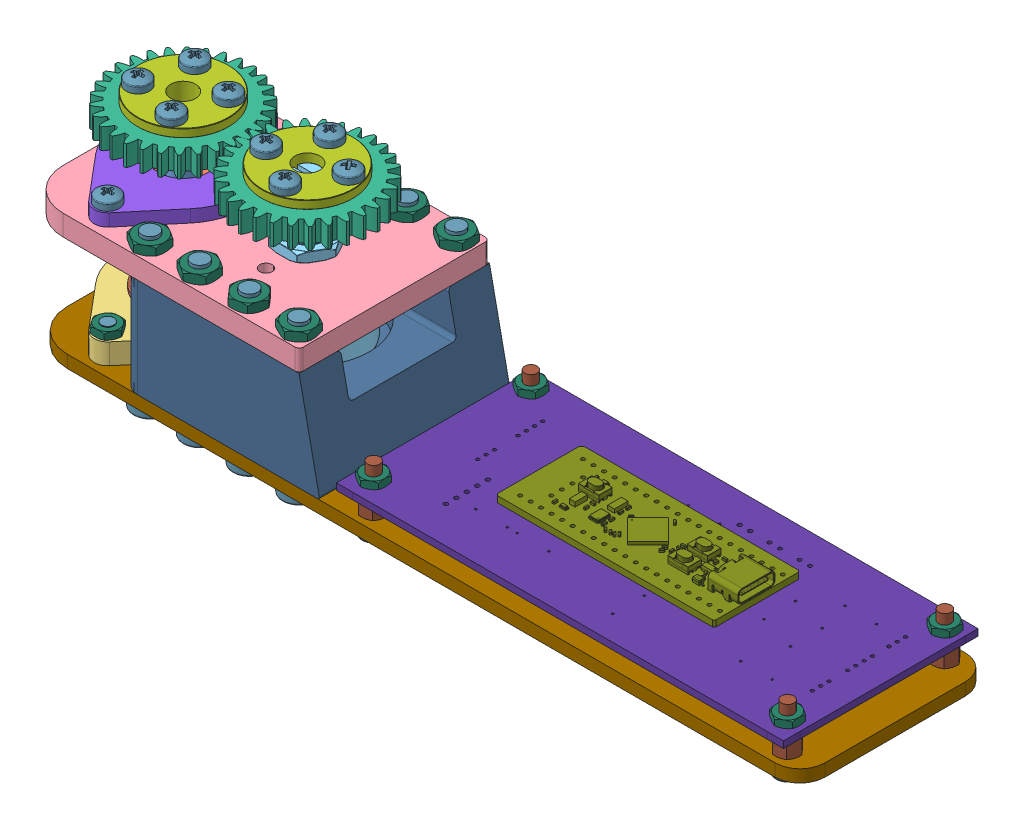
SolidWorks assembly phan_cang_tay_asm, configuration Default. Lengths in mm.
Overall size (193.86 57.82 47.69).
87 component instances, 17 part files, 172 mates.
Components (placement in the parent):
- truc_khuy_tay_6mm-1: truc_khuy_tay_6mm [Default] at (-13.0536 7.0359 41.2843) size (6 45 6)
- instrument ball bearing_68_am-1: instrument ball bearing_68_am [AFBMA 12.1.4.1 - 0060-19 - 8,DE,NC,8_68] at (-13.0536 10.0359 41.2843) x (0 -1 0) z (0.814441 0 0.580247) size (6 19 19)
- instrument ball bearing_68_am-2: instrument ball bearing_68_am [AFBMA 12.1.4.1 - 0060-19 - 8,DE,NC,8_68] at (-13.0536 33.0359 41.2843) x (0 -1 0) z (0.463151 0 0.88628) size (6 19 19)
- thanh_noi_cang_tay_1-1: thanh_noi_cang_tay_1 [Default] at (-13.0536 7.0359 41.2843) x (-1 0 0) z (0 0 -1) size (30 5 43)
- khuy_tay-1: khuy_tay [Default] at (16.9464 36.0359 41.2843) x (-1 0 0) z (0 -1 0) size (67 46 5)
- RV24 v6.step-1: RV24 v6.step [Default] at (16.9464 24.0359 41.2843) x (0 1 0) z (0 0 -1) size (34 30.6 24.6)
- banh_rang-1: banh_rang [Default] at (-13.8942 39.1454 73.2027) x (0 1 0) z (-0.508693 0 -0.860948) size (12 31.88 32)
  - spur gear_iso_m3-1: spur gear_iso_m3 [ISO - Spur gear 1M 30T 20PA 10FW ---S30B25H18L6.0N] at (1.8905 16.9604 27.0525) size (5 31.88 32)
  - mat_bich_6mm-1: mat_bich_6mm [Default] at (13.8905 16.9604 27.0525) x (0 0 1) z (0 -1 0) size (22 12 22)
- mieng_che_o_lan-1: mieng_che_o_lan [Default] at (-13.0536 36.0359 41.2843) x (-1 0 0) z (0 0 -1) size (30 3 43)
- thanh_cang_tay-1: thanh_cang_tay [Default] at (102.9464 4.0359 41.2843) x (-1 0 0) z (0 1 0) size (187 46 3)
- noi_cang_tay-1: noi_cang_tay [Default] at (21.9464 7.0359 41.2843) x (-1 0 0) z (0 0 -1) size (47.89 24 46)
- hexagonal_spacer_MF_M3_H05_HEX5_FTD3_MTL8.step-2: hexagonal_spacer_MF_M3_H05_HEX5_FTD3_MTL8.step [Default] at (151.9464 12.0359 60.2843) x (-0.310043 0 0.950723) z (0 -1 0) size (5.78 5.01 10.97)
- mieng_dem_cang_tay-1: mieng_dem_cang_tay [Default] at (117.9464 4.0359 41.2843) x (-1 0 0) z (0 0 -1) size (70 6.47 35)
- mieng_dem_cang_tay_2-1: mieng_dem_cang_tay_2 [Default] at (30.9464 4.0359 41.2843) x (-1 0 0) z (0 0 -1) size (68 6.47 30)
- pan head cross recess screw_iso-1: pan head cross recess screw_iso [ISO 7045 - M3 x 8 - Z - 8N] at (147.9464 -0.3641 27.2843) x (0 1 0) z (0 0 1) size (10.35 5.6 5.6)
- pan head cross recess screw_iso-2: pan head cross recess screw_iso [ISO 7045 - M3 x 8 - Z - 8N] at (147.9464 -0.3641 55.2843) x (0 1 0) z (0 0 1) size (10.35 5.6 5.6)
- pan head cross recess screw_iso-3: pan head cross recess screw_iso [ISO 7045 - M3 x 8 - Z - 8N] at (87.9464 -0.3641 55.2843) x (0 1 0) z (0 0 1) size (10.35 5.6 5.6)
- pan head cross recess screw_iso-4: pan head cross recess screw_iso [ISO 7045 - M3 x 8 - Z - 8N] at (87.9464 -0.3641 27.2843) x (0 1 0) z (0 0 1) size (10.35 5.6 5.6)
- pan head cross recess screw_iso-5: pan head cross recess screw_iso [ISO 7045 - M3 x 8 - Z - 8N] at (60.9464 -0.3641 52.2843) x (0 1 0) z (0 0 1) size (10.35 5.6 5.6)
- pan head cross recess screw_iso-6: pan head cross recess screw_iso [ISO 7045 - M3 x 8 - Z - 8N] at (60.9464 -0.3641 30.2843) x (0 1 0) z (0 0 1) size (10.35 5.6 5.6)
- pan head cross recess screw_iso-9: pan head cross recess screw_iso [ISO 7045 - M3 x 6 - Z - 6N] at (0.9464 9.4359 30.2843) x (0 -1 0) z (0 0 1) size (8.35 5.6 5.6)
- pan head cross recess screw_iso-10: pan head cross recess screw_iso [ISO 7045 - M3 x 6 - Z - 6N] at (0.9464 9.4359 52.2843) x (0 -1 0) z (0 0 1) size (8.35 5.6 5.6)
- hex thin nut chamfered gradeab_iso-3: hex thin nut chamfered gradeab_iso [ISO - 4035 - M3 - N] at (0.9464 0.2359 30.2843) x (1 0 0) z (0 -1 0) size (5.5 6.35 1.8)
- hex thin nut chamfered gradeab_iso-4: hex thin nut chamfered gradeab_iso [ISO - 4035 - M3 - N] at (0.9464 0.2359 52.2843) x (1 0 0) z (0 -1 0) size (5.5 6.35 1.8)
- hex thin nut chamfered gradeab_iso-5: hex thin nut chamfered gradeab_iso [ISO - 4035 - M3 - N] at (60.9464 8.8359 30.2843) x (1 0 0) z (0 1 0) size (5.5 6.35 1.8)
- hex thin nut chamfered gradeab_iso-6: hex thin nut chamfered gradeab_iso [ISO - 4035 - M3 - N] at (60.9464 8.8359 52.2843) x (1 0 0) z (0 1 0) size (5.5 6.35 1.8)
- hex thin nut chamfered gradeab_iso-7: hex thin nut chamfered gradeab_iso [ISO - 4035 - M3 - N] at (87.9464 8.8359 55.2843) x (1 0 0) z (0 1 0) size (5.5 6.35 1.8)
- hex thin nut chamfered gradeab_iso-8: hex thin nut chamfered gradeab_iso [ISO - 4035 - M3 - N] at (87.9464 8.8359 27.2843) x (1 0 0) z (0 1 0) size (5.5 6.35 1.8)
- hex thin nut chamfered gradeab_iso-9: hex thin nut chamfered gradeab_iso [ISO - 4035 - M3 - N] at (147.9464 8.8359 27.2843) x (1 0 0) z (0 1 0) size (5.5 6.35 1.8)
- hex thin nut chamfered gradeab_iso-10: hex thin nut chamfered gradeab_iso [ISO - 4035 - M3 - N] at (147.9464 8.8359 55.2843) x (1 0 0) z (0 1 0) size (5.5 6.35 1.8)
- pan head cross recess screw_iso-18: pan head cross recess screw_iso [ISO 7045 - M4 x 35 - Z - 35N] at (33.9464 0.9359 22.2843) x (0 1 0) z (0 0 1) size (38.02 8 8)
- pan head cross recess screw_iso-19: pan head cross recess screw_iso [ISO 7045 - M4 x 35 - Z - 35N] at (21.9464 0.9359 22.2843) x (0 1 0) z (0 0 1) size (38.02 8 8)
- pan head cross recess screw_iso-20: pan head cross recess screw_iso [ISO 7045 - M4 x 35 - Z - 35N] at (9.9464 0.9359 22.2843) x (0 1 0) z (0 0 1) size (38.02 8 8)
- pan head cross recess screw_iso-21: pan head cross recess screw_iso [ISO 7045 - M4 x 35 - Z - 35N] at (33.9464 0.9359 60.2843) x (0 1 0) z (0 0 1) size (38.02 8 8)
- pan head cross recess screw_iso-22: pan head cross recess screw_iso [ISO 7045 - M4 x 35 - Z - 35N] at (21.9464 0.9359 60.2843) x (0 1 0) z (0 0 1) size (38.02 8 8)
- pan head cross recess screw_iso-23: pan head cross recess screw_iso [ISO 7045 - M4 x 35 - Z - 35N] at (9.9464 0.9359 60.2843) x (0 1 0) z (0.916024 0 0.401125) size (38.02 8 8)
- hex thin nut chamfered gradeab_iso-11: hex thin nut chamfered gradeab_iso [ISO - 4035 - M4 - N] at (33.9464 38.2359 22.2843) x (1 0 0) z (0 1 0) size (7 8.08 2.2)
- hex thin nut chamfered gradeab_iso-12: hex thin nut chamfered gradeab_iso [ISO - 4035 - M4 - N] at (21.9464 38.2359 22.2843) x (1 0 0) z (0 1 0) size (7 8.08 2.2)
- hex thin nut chamfered gradeab_iso-13: hex thin nut chamfered gradeab_iso [ISO - 4035 - M4 - N] at (9.9464 38.2359 22.2843) x (1 0 0) z (0 1 0) size (7 8.08 2.2)
- hex thin nut chamfered gradeab_iso-14: hex thin nut chamfered gradeab_iso [ISO - 4035 - M4 - N] at (33.9464 36.0359 60.2843) x (0.993976 0 -0.109599) z (0 -1 0) size (7 8.08 2.2)
- hex thin nut chamfered gradeab_iso-15: hex thin nut chamfered gradeab_iso [ISO - 4035 - M4 - N] at (21.9464 38.2359 60.2843) x (-0.185733 0 -0.9826) z (0 1 0) size (7 8.08 2.2)
- hex thin nut chamfered gradeab_iso-16: hex thin nut chamfered gradeab_iso [ISO - 4035 - M4 - N] at (9.9464 38.2359 60.2843) x (1 0 0) z (0 1 0) size (7 8.08 2.2)
- pan head cross recess screw_iso-25: pan head cross recess screw_iso [ISO 7045 - M3 x 10 - Z - 10N] at (-6.166 55.4359 37.2148) x (0 -1 0) z (0 0 1) size (12.35 5.6 5.6)
- pan head cross recess screw_iso-26: pan head cross recess screw_iso [ISO 7045 - M3 x 10 - Z - 10N] at (-8.9841 55.4359 48.1719) x (0 -1 0) z (0 0 1) size (12.35 5.6 5.6)
- pan head cross recess screw_iso-27: pan head cross recess screw_iso [ISO 7045 - M3 x 10 - Z - 10N] at (-19.9412 55.4359 45.3539) x (0 -1 0) z (-0.140483 0 -0.990083) size (12.35 5.6 5.6)
- pan head cross recess screw_iso-28: pan head cross recess screw_iso [ISO 7045 - M3 x 10 - Z - 10N] at (-17.1232 55.4359 34.3967) x (0 -1 0) z (0 0 1) size (12.35 5.6 5.6)
- pan head cross recess screw_iso-29: pan head cross recess screw_iso [ISO 7045 - M3 x 10 - Z - 10N] at (24.6096 55.4359 38.9877) x (0 -1 0) z (-0.805474 0 0.592631) size (12.35 5.6 5.6)
- pan head cross recess screw_iso-30: pan head cross recess screw_iso [ISO 7045 - M3 x 10 - Z - 10N] at (14.6497 55.4359 33.6211) x (0 -1 0) z (0 0 1) size (12.35 5.6 5.6)
- pan head cross recess screw_iso-31: pan head cross recess screw_iso [ISO 7045 - M3 x 10 - Z - 10N] at (9.2831 55.4359 43.581) x (0 -1 0) z (0 0 1) size (12.35 5.6 5.6)
- pan head cross recess screw_iso-32: pan head cross recess screw_iso [ISO 7045 - M3 x 10 - Z - 10N] at (19.243 55.4359 48.9476) x (0 -1 0) z (0 0 1) size (12.35 5.6 5.6)
- banh_rang-3: banh_rang [Default] at (47.7291 39.1454 49.7644) x (0 1 0) z (-0.957906 0 0.287083) size (12 31.88 32)
  - spur gear_iso_m3-1: spur gear_iso_m3 [ISO - Spur gear 1M 30T 20PA 10FW ---S30B25H18L6.0N] at (1.8905 16.9604 27.0525) size (5 31.88 32)
  - mat_bich_6mm-1: mat_bich_6mm [Default] at (13.8905 16.9604 27.0525) x (0 0 1) z (0 -1 0) size (22 12 22)
- hex thin nut chamfered gradeab_iso-18: hex thin nut chamfered gradeab_iso [ISO - 4035 - M3 - N] at (19.243 44.2359 48.9476) x (1 0 0) z (0 -1 0) size (5.5 6.35 1.8)
- hex thin nut chamfered gradeab_iso-19: hex thin nut chamfered gradeab_iso [ISO - 4035 - M3 - N] at (9.2831 44.2359 43.581) x (1 0 0) z (0 -1 0) size (5.5 6.35 1.8)
- hex thin nut chamfered gradeab_iso-20: hex thin nut chamfered gradeab_iso [ISO - 4035 - M3 - N] at (14.6497 44.2359 33.6211) x (1 0 0) z (0 -1 0) size (5.5 6.35 1.8)
- hex thin nut chamfered gradeab_iso-21: hex thin nut chamfered gradeab_iso [ISO - 4035 - M3 - N] at (24.6096 44.2359 38.9877) x (1 0 0) z (0 -1 0) size (5.5 6.35 1.8)
- hex thin nut chamfered gradeab_iso-22: hex thin nut chamfered gradeab_iso [ISO - 4035 - M3 - N] at (-6.166 44.2359 37.2148) x (1 0 0) z (0 -1 0) size (5.5 6.35 1.8)
- hex thin nut chamfered gradeab_iso-23: hex thin nut chamfered gradeab_iso [ISO - 4035 - M3 - N] at (-8.9841 44.2359 48.1719) x (1 0 0) z (0 -1 0) size (5.5 6.35 1.8)
- hex thin nut chamfered gradeab_iso-24: hex thin nut chamfered gradeab_iso [ISO - 4035 - M3 - N] at (-17.1232 44.2359 34.3967) x (1 0 0) z (0 -1 0) size (5.5 6.35 1.8)
- hex thin nut chamfered gradeab_iso-25: hex thin nut chamfered gradeab_iso [ISO - 4035 - M3 - N] at (-19.9412 44.2359 45.3539) x (1 0 0) z (0 -1 0) size (5.5 6.35 1.8)
- pan head cross recess screw_iso-37: pan head cross recess screw_iso [ISO 7045 - M3 x 10 - Z - 10N] at (-13.0536 41.4359 59.5343) x (0 -1 0) z (0 0 1) size (12.35 5.6 5.6)
- pan head cross recess screw_iso-38: pan head cross recess screw_iso [ISO 7045 - M3 x 10 - Z - 10N] at (-13.0536 41.4359 23.0343) x (0 -1 0) z (0 0 1) size (12.35 5.6 5.6)
- pan head cross recess screw_iso-39: pan head cross recess screw_iso [ISO 7045 - M3 x 10 - Z - 10N] at (-13.0536 1.6359 59.5343) x (0 1 0) z (0 0 1) size (12.35 5.6 5.6)
- pan head cross recess screw_iso-40: pan head cross recess screw_iso [ISO 7045 - M3 x 10 - Z - 10N] at (-13.0536 1.6359 23.0343) x (0 1 0) z (0 0 1) size (12.35 5.6 5.6)
- hex thin nut chamfered gradeab_iso-30: hex thin nut chamfered gradeab_iso [ISO - 4035 - M3 - N] at (-13.0536 29.2359 23.0343) x (1 0 0) z (0 -1 0) size (5.5 6.35 1.8)
- hex thin nut chamfered gradeab_iso-31: hex thin nut chamfered gradeab_iso [ISO - 4035 - M3 - N] at (-13.0536 13.8359 23.0343) x (1 0 0) z (0 1 0) size (5.5 6.35 1.8)
- hex thin nut chamfered gradeab_iso-33: hex thin nut chamfered gradeab_iso [ISO - 4035 - M3 - N] at (-13.0536 12.0359 59.5343) x (0.832178 0 -0.554509) z (0 -1 0) size (5.5 6.35 1.8)
- hex thin nut chamfered gradeab_iso-34: hex thin nut chamfered gradeab_iso [ISO - 4035 - M3 - N] at (-13.0536 29.2359 59.5343) x (1 0 0) z (0 -1 0) size (5.5 6.35 1.8)
- pan head cross recess screw_iso-59: pan head cross recess screw_iso [ISO 7045 - M4 x 35 - Z - 35N] at (-2.0536 0.9359 60.2843) x (0 1 0) z (-0.660079 0 0.751196) size (38.02 8 8)
- hex thin nut chamfered gradeab_iso-45: hex thin nut chamfered gradeab_iso [ISO - 4035 - M4 - N] at (-2.0536 38.2359 60.2843) x (1 0 0) z (0 1 0) size (7 8.08 2.2)
- hexagonal_spacer_MF_M3_H05_HEX5_FTD3_MTL8.step-3: hexagonal_spacer_MF_M3_H05_HEX5_FTD3_MTL8.step [Default] at (151.9464 12.0359 22.2843) x (-0.310043 0 0.950723) z (0 -1 0) size (5.78 5.01 10.97)
- hexagonal_spacer_MF_M3_H05_HEX5_FTD3_MTL8.step-4: hexagonal_spacer_MF_M3_H05_HEX5_FTD3_MTL8.step [Default] at (51.9464 12.0359 60.2843) x (-0.310043 0 0.950723) z (0 -1 0) size (5.78 5.01 10.97)
- hexagonal_spacer_MF_M3_H05_HEX5_FTD3_MTL8.step-5: hexagonal_spacer_MF_M3_H05_HEX5_FTD3_MTL8.step [Default] at (51.9464 12.0359 22.2843) x (-0.310043 0 0.950723) z (0 -1 0) size (5.78 5.01 10.97)
- pan head cross recess screw_iso-60: pan head cross recess screw_iso [ISO 7045 - M3 x 8 - Z - 8N] at (151.9464 1.6359 22.2843) x (0 1 0) z (0 0 1) size (10.35 5.6 5.6)
- pan head cross recess screw_iso-61: pan head cross recess screw_iso [ISO 7045 - M3 x 8 - Z - 8N] at (151.9464 1.6359 60.2843) x (0 1 0) z (0 0 1) size (10.35 5.6 5.6)
- pan head cross recess screw_iso-62: pan head cross recess screw_iso [ISO 7045 - M3 x 8 - Z - 8N] at (51.9464 1.6359 60.2843) x (0 1 0) z (0 0 1) size (10.35 5.6 5.6)
- pan head cross recess screw_iso-63: pan head cross recess screw_iso [ISO 7045 - M3 x 8 - Z - 8N] at (51.9464 1.6359 22.2843) x (0 1 0) z (0 0 1) size (10.35 5.6 5.6)
- control_glove_v0.1.step-1: control_glove_v0.1.step [Default] at (56.9464 12.0359 56.2843) x (1 0 0) z (0 1 0) size (108 47 7.4)
  - MiniF4x1Cx_V31_3D.step-1: MiniF4x1Cx_V31_3D.step [Default] at (68.0647 25.992 4.15) x (-1 0 0) z (0 0 1) size (52.81 20.78 5.3)
    - COMPOUND.step-1: COMPOUND.step [Default] at origin size (52.81 20.78 5.3)
  - _autosave-control_glove_v0.1 PCB.step-1: _autosave-control_glove_v0.1 PCB.step [Default] at origin size (108 47 1.6)
- hex thin nut chamfered gradeab_iso-46: hex thin nut chamfered gradeab_iso [ISO - 4035 - M3 - N] at (51.9464 15.4359 22.2843) x (1 0 0) z (0 1 0) size (5.5 6.35 1.8)
- hex thin nut chamfered gradeab_iso-47: hex thin nut chamfered gradeab_iso [ISO - 4035 - M3 - N] at (51.9464 15.4359 60.2843) x (1 0 0) z (0 1 0) size (5.5 6.35 1.8)
- hex thin nut chamfered gradeab_iso-48: hex thin nut chamfered gradeab_iso [ISO - 4035 - M3 - N] at (151.9464 15.4359 22.2843) x (1 0 0) z (0 1 0) size (5.5 6.35 1.8)
- hex thin nut chamfered gradeab_iso-49: hex thin nut chamfered gradeab_iso [ISO - 4035 - M3 - N] at (151.9464 15.4359 60.2843) x (1 0 0) z (0 1 0) size (5.5 6.35 1.8)
Mates (geometry in assembly coordinates):
- Concentric11: concentric aligned: cylinder of truc_khuy_tay_6mm-1 through (-13.0536 52.0359 41.2843) axis (0 -1 0) radius 3; cylinder of instrument ball bearing_68_am-1 through (-13.0536 30.6734 41.2843) axis (0 -1 0) radius 3
- Coincident1: coincident aligned: plane of truc_khuy_tay_6mm-1 through (-13.0536 7.0359 41.2843) normal (0 -1 0); plane of instrument ball bearing_68_am-1 through (-11.1388 7.0359 38.5967) normal (0 -1 0)
- Concentric6: concentric aligned: cylinder of truc_khuy_tay_6mm-1 through (-13.0536 52.0359 41.2843) axis (0 -1 0) radius 3; cylinder of instrument ball bearing_68_am-2 through (-13.0536 53.6734 41.2843) axis (0 -1 0) radius 3
- Concentric8: concentric aligned: cylinder of instrument ball bearing_68_am-1 through (-13.0536 30.6734 41.2843) axis (0 -1 0) radius 9.5; cylinder of thanh_noi_cang_tay_1-1 through (-13.0536 12.0359 41.2843) axis (0 -1 0) radius 9.5
- Concentric9: concentric anti-aligned: cylinder of instrument ball bearing_68_am-2 through (-13.0536 53.6734 41.2843) axis (0 -1 0) radius 9.5; cylinder of khuy_tay-1 through (-13.0536 31.0359 41.2843) axis (0 1 0) radius 9.5
- Concentric10: concentric aligned: cylinder of khuy_tay-1 through (16.9464 31.0359 41.2843) axis (0 1 0) radius 4.6; cylinder of RV24 v6.step-1 through (16.9464 41.0359 41.2843) axis (0 1 0) radius 3
- Distance2: distance = 19 mm anti-aligned: plane of thanh_noi_cang_tay_1-1 through (-13.0536 12.0359 41.2843) normal (0 1 0); plane of khuy_tay-1 through (16.9464 31.0359 41.2843) normal (0 -1 0)
- Concentric16: concentric aligned: cylinder of truc_khuy_tay_6mm-1 through (-13.0536 52.0359 41.2843) axis (0 -1 0) radius 3; cylinder of banh_rang-1/6mm Rigid Flange Coupling v2.step-1 through (-13.0536 50.0359 41.2843) axis (0 -1 0) radius 3
- Coincident34: coincident aligned: plane of instrument ball bearing_68_am-1 through (-7.7154 7.0359 33.7915) normal (0 -1 0); plane of thanh_noi_cang_tay_1-1 through (-13.0536 7.0359 41.2843) normal (0 -1 0)
- Concentric21: concentric aligned: cylinder of truc_khuy_tay_6mm-1 through (-13.0536 52.0359 41.2843) axis (0 -1 0) radius 3; cylinder of mieng_che_o_lan-1 through (-13.0536 39.0359 41.2843) axis (0 -1 0) radius 6
- Coincident35: coincident anti-aligned: plane of thanh_noi_cang_tay_1-1 through (-13.0536 7.0359 41.2843) normal (0 -1 0); plane of thanh_cang_tay-1 through (102.9464 7.0359 41.2843) normal (0 1 0)
- Concentric22: concentric anti-aligned: cylinder of thanh_noi_cang_tay_1-1 through (-13.0536 12.0359 41.2843) axis (0 -1 0) radius 15; cylinder of thanh_cang_tay-1 through (-13.0536 4.0359 41.2843) axis (0 1 0) radius 6
- Parallel8: parallel aligned: plane of RV24 v6.step-1 through (33.7464 28.5359 41.7843) normal (0 0 -1); plane of thanh_cang_tay-1 through (102.9464 7.0359 18.2843) normal (0 0 -1)
- Coincident46: coincident anti-aligned: plane of thanh_cang_tay-1 through (102.9464 7.0359 41.2843) normal (0 1 0); plane of noi_cang_tay-1 through (21.9464 7.0359 41.2843) normal (0 -1 0)
- Concentric40: concentric anti-aligned: cylinder of khuy_tay-1 through (-13.0536 31.0359 23.0343) axis (0 1 0) radius 1.5; cylinder of mieng_che_o_lan-1 through (-13.0536 39.0359 23.0343) axis (0 -1 0) radius 1.5
- Coincident50: coincident anti-aligned: plane of khuy_tay-1 through (16.9464 36.0359 41.2843) normal (0 1 0); plane of mieng_che_o_lan-1 through (-13.0536 36.0359 41.2843) normal (0 -1 0)
- Concentric41: concentric anti-aligned: cylinder of truc_khuy_tay_6mm-1 through (-13.0536 52.0359 41.2843) axis (0 -1 0) radius 3; cylinder of banh_rang-1/mat_bich_6mm-1 through (-13.0536 51.0359 41.2843) axis (0 1 0) radius 3
- Coincident52: coincident anti-aligned: plane of khuy_tay-1 through (16.9464 31.0359 41.2843) normal (0 -1 0); plane of RV24 v6.step-1 through (16.9667 31.0359 41.2843) normal (0 1 0)
- Coincident55: coincident anti-aligned: plane of instrument ball bearing_68_am-2 through (-6.3622 36.0359 37.7875) normal (0 1 0); plane of mieng_che_o_lan-1 through (-13.0536 36.0359 41.2843) normal (0 -1 0)
- Concentric51: concentric aligned: cylinder of khuy_tay-1 through (33.9464 41.0359 22.2843) axis (0 -1 0) radius 2; cylinder of noi_cang_tay-1 through (33.9464 31.0359 22.2843) axis (0 -1 0) radius 2
- Coincident57: coincident anti-aligned: plane of thanh_cang_tay-1 through (102.9464 7.0359 41.2843) normal (0 1 0); plane of noi_cang_tay-1 through (21.9464 7.0359 41.2843) normal (0 -1 0)
- Parallel9: parallel aligned: plane of thanh_cang_tay-1 through (102.9464 7.0359 64.2843) normal (0 0 1); plane of noi_cang_tay-1 through (21.9464 31.0359 64.2843) normal (0 0 1)
- Parallel11: parallel aligned: plane of khuy_tay-1 through (37.9464 36.0359 41.2843) normal (1 0 0); plane of thanh_cang_tay-1 through (158.9464 7.0359 41.2843) normal (1 0 0)
- Concentric54: concentric anti-aligned: cylinder of thanh_noi_cang_tay_1-1 through (-13.0536 12.0359 23.0343) axis (0 -1 0) radius 1.5; cylinder of thanh_cang_tay-1 through (-13.0536 4.0359 23.0343) axis (0 1 0) radius 1.5
- Concentric59: concentric anti-aligned: cylinder of thanh_cang_tay-1 through (151.9464 4.0359 60.2843) axis (0 1 0) radius 1.5; cylinder of hexagonal_spacer_MF_M3_H05_HEX5_FTD3_MTL8.step-2 through (151.9464 19.8569 60.2843) axis (0 -1 0) radius 1.5
- Coincident72: coincident anti-aligned: plane of thanh_cang_tay-1 through (102.9464 7.0359 41.2843) normal (0 1 0); plane of hexagonal_spacer_MF_M3_H05_HEX5_FTD3_MTL8.step-2 through (151.9464 7.0359 60.2843) normal (0 -1 0)
- Parallel16: parallel aligned: plane of thanh_cang_tay-1 through (158.9464 7.0359 41.2843) normal (1 0 0); plane of mieng_dem_cang_tay-1 through (152.9464 4.0359 41.2843) normal (1 0 0)
- Coincident77: coincident anti-aligned: plane of thanh_cang_tay-1 through (102.9464 4.0359 41.2843) normal (0 -1 0); plane of mieng_dem_cang_tay-1 through (117.9464 4.0359 41.2843) normal (0 1 0)
- Concentric62: concentric anti-aligned: cylinder of thanh_cang_tay-1 through (147.9464 7.0359 27.2843) axis (0 -1 0) radius 1.6; cylinder of mieng_dem_cang_tay-1 through (147.9464 -5.9641 27.2843) axis (0 1 0) radius 1.5
- Concentric63: concentric anti-aligned: cylinder of thanh_cang_tay-1 through (60.9464 7.0359 30.2843) axis (0 -1 0) radius 1.5; cylinder of mieng_dem_cang_tay_2-1 through (60.9464 -5.9641 30.2843) axis (0 1 0) radius 1.5
- Parallel17: parallel aligned: plane of thanh_cang_tay-1 through (158.9464 7.0359 41.2843) normal (1 0 0); plane of mieng_dem_cang_tay_2-1 through (64.9464 4.0359 41.2843) normal (1 0 0)
- Coincident80: coincident anti-aligned: plane of thanh_cang_tay-1 through (102.9464 4.0359 41.2843) normal (0 -1 0); plane of mieng_dem_cang_tay_2-1 through (30.9464 4.0359 41.2843) normal (0 1 0)
- Concentric85: concentric anti-aligned: cylinder of mieng_dem_cang_tay-1 through (147.9464 -5.9641 27.2843) axis (0 1 0) radius 1.5; cylinder of pan head cross recess screw_iso-1 through (147.9464 -25.7641 27.2843) axis (0 -1 0) radius 2.8
- Coincident88: coincident anti-aligned: plane of mieng_dem_cang_tay-1 through (152.9464 2.0359 41.2843) normal (0 -1 0); plane of pan head cross recess screw_iso-1 through (146.4464 2.0359 27.2843) normal (0 1 0)
- Concentric86: concentric anti-aligned: cylinder of mieng_dem_cang_tay-1 through (147.9464 -5.9641 55.2843) axis (0 1 0) radius 1.5; cylinder of pan head cross recess screw_iso-2 through (147.9464 -25.7641 55.2843) axis (0 -1 0) radius 2.8
- Coincident89: coincident anti-aligned: plane of mieng_dem_cang_tay-1 through (152.9464 2.0359 41.2843) normal (0 -1 0); plane of pan head cross recess screw_iso-2 through (146.4464 2.0359 55.2843) normal (0 1 0)
- Concentric87: concentric anti-aligned: cylinder of mieng_dem_cang_tay-1 through (87.9464 -5.9641 55.2843) axis (0 1 0) radius 1.5; cylinder of pan head cross recess screw_iso-3 through (87.9464 -25.7641 55.2843) axis (0 -1 0) radius 2.8
- Coincident90: coincident anti-aligned: plane of mieng_dem_cang_tay-1 through (82.9464 2.0359 41.2843) normal (0 -1 0); plane of pan head cross recess screw_iso-3 through (86.4464 2.0359 55.2843) normal (0 1 0)
- Concentric88: concentric anti-aligned: cylinder of mieng_dem_cang_tay-1 through (87.9464 -5.9641 27.2843) axis (0 1 0) radius 1.5; cylinder of pan head cross recess screw_iso-4 through (87.9464 -25.7641 27.2843) axis (0 -1 0) radius 2.8
- Coincident91: coincident anti-aligned: plane of mieng_dem_cang_tay-1 through (82.9464 2.0359 41.2843) normal (0 -1 0); plane of pan head cross recess screw_iso-4 through (86.4464 2.0359 27.2843) normal (0 1 0)
- Concentric89: concentric anti-aligned: cylinder of mieng_dem_cang_tay_2-1 through (60.9464 -5.9641 52.2843) axis (0 1 0) radius 1.5; cylinder of pan head cross recess screw_iso-5 through (60.9464 -25.7641 52.2843) axis (0 -1 0) radius 2.8
- Coincident92: coincident anti-aligned: plane of mieng_dem_cang_tay_2-1 through (64.9464 2.0359 41.2843) normal (0 -1 0); plane of pan head cross recess screw_iso-5 through (59.4464 2.0359 52.2843) normal (0 1 0)
- Concentric90: concentric anti-aligned: cylinder of mieng_dem_cang_tay_2-1 through (60.9464 -5.9641 30.2843) axis (0 1 0) radius 1.5; cylinder of pan head cross recess screw_iso-6 through (60.9464 -25.7641 30.2843) axis (0 -1 0) radius 2.8
- Coincident93: coincident anti-aligned: plane of mieng_dem_cang_tay_2-1 through (64.9464 2.0359 41.2843) normal (0 -1 0); plane of pan head cross recess screw_iso-6 through (59.4464 2.0359 30.2843) normal (0 1 0)
- Concentric93: concentric anti-aligned: cylinder of thanh_cang_tay-1 through (0.9464 14.0359 30.2843) axis (0 -1 0) radius 1.5; cylinder of pan head cross recess screw_iso-9 through (0.9464 34.8359 30.2843) axis (0 1 0) radius 2.8
- Coincident96: coincident anti-aligned: plane of thanh_cang_tay-1 through (102.9464 7.0359 41.2843) normal (0 1 0); plane of pan head cross recess screw_iso-9 through (2.4464 7.0359 30.2843) normal (0 -1 0)
- Concentric94: concentric anti-aligned: cylinder of thanh_cang_tay-1 through (0.9464 14.0359 52.2843) axis (0 -1 0) radius 1.5; cylinder of pan head cross recess screw_iso-10 through (0.9464 34.8359 52.2843) axis (0 1 0) radius 2.8
- Coincident97: coincident anti-aligned: plane of thanh_cang_tay-1 through (102.9464 7.0359 41.2843) normal (0 1 0); plane of pan head cross recess screw_iso-10 through (2.4464 7.0359 52.2843) normal (0 -1 0)
- Concentric96: concentric anti-aligned: cylinder of mieng_dem_cang_tay_2-1 through (0.9464 -5.9641 30.2843) axis (0 1 0) radius 1.5; cylinder of hex thin nut chamfered gradeab_iso-3 through (0.9464 25.2734 30.2843) axis (0 -1 0) radius 1.5
- Coincident99: coincident anti-aligned: plane of mieng_dem_cang_tay_2-1 through (-3.0536 2.0359 41.2843) normal (0 -1 0); plane of hex thin nut chamfered gradeab_iso-3 through (0.9464 2.0359 33.4598) normal (0 1 0)
- Concentric97: concentric anti-aligned: cylinder of mieng_dem_cang_tay_2-1 through (0.9464 -5.9641 52.2843) axis (0 1 0) radius 1.5; cylinder of hex thin nut chamfered gradeab_iso-4 through (0.9464 25.2734 52.2843) axis (0 -1 0) radius 1.5
- Coincident100: coincident anti-aligned: plane of mieng_dem_cang_tay_2-1 through (-3.0536 2.0359 41.2843) normal (0 -1 0); plane of hex thin nut chamfered gradeab_iso-4 through (0.9464 2.0359 55.4598) normal (0 1 0)
- Concentric98: concentric anti-aligned: cylinder of thanh_cang_tay-1 through (60.9464 7.0359 30.2843) axis (0 -1 0) radius 1.5; cylinder of hex thin nut chamfered gradeab_iso-5 through (60.9464 -16.2016 30.2843) axis (0 1 0) radius 1.5
- Coincident101: coincident anti-aligned: plane of thanh_cang_tay-1 through (102.9464 7.0359 41.2843) normal (0 1 0); plane of hex thin nut chamfered gradeab_iso-5 through (60.9464 7.0359 27.1089) normal (0 -1 0)
- Concentric99: concentric anti-aligned: cylinder of thanh_cang_tay-1 through (60.9464 7.0359 52.2843) axis (0 -1 0) radius 1.5; cylinder of hex thin nut chamfered gradeab_iso-6 through (60.9464 -16.2016 52.2843) axis (0 1 0) radius 1.5
- Coincident102: coincident anti-aligned: plane of thanh_cang_tay-1 through (102.9464 7.0359 41.2843) normal (0 1 0); plane of hex thin nut chamfered gradeab_iso-6 through (60.9464 7.0359 49.1089) normal (0 -1 0)
- Concentric100: concentric anti-aligned: cylinder of thanh_cang_tay-1 through (87.9464 7.0359 55.2843) axis (0 -1 0) radius 1.6; cylinder of hex thin nut chamfered gradeab_iso-7 through (87.9464 -16.2016 55.2843) axis (0 1 0) radius 1.5
- Coincident103: coincident anti-aligned: plane of thanh_cang_tay-1 through (102.9464 7.0359 41.2843) normal (0 1 0); plane of hex thin nut chamfered gradeab_iso-7 through (87.9464 7.0359 52.1089) normal (0 -1 0)
- Concentric101: concentric anti-aligned: cylinder of thanh_cang_tay-1 through (87.9464 7.0359 27.2843) axis (0 -1 0) radius 1.6; cylinder of hex thin nut chamfered gradeab_iso-8 through (87.9464 -16.2016 27.2843) axis (0 1 0) radius 1.5
- Coincident104: coincident anti-aligned: plane of thanh_cang_tay-1 through (102.9464 7.0359 41.2843) normal (0 1 0); plane of hex thin nut chamfered gradeab_iso-8 through (87.9464 7.0359 24.1089) normal (0 -1 0)
- Concentric102: concentric anti-aligned: cylinder of thanh_cang_tay-1 through (147.9464 7.0359 27.2843) axis (0 -1 0) radius 1.6; cylinder of hex thin nut chamfered gradeab_iso-9 through (147.9464 -16.2016 27.2843) axis (0 1 0) radius 1.5
- Coincident105: coincident anti-aligned: plane of thanh_cang_tay-1 through (102.9464 7.0359 41.2843) normal (0 1 0); plane of hex thin nut chamfered gradeab_iso-9 through (147.9464 7.0359 24.1089) normal (0 -1 0)
- Concentric103: concentric anti-aligned: cylinder of thanh_cang_tay-1 through (147.9464 7.0359 55.2843) axis (0 -1 0) radius 1.6; cylinder of hex thin nut chamfered gradeab_iso-10 through (147.9464 -16.2016 55.2843) axis (0 1 0) radius 1.5
- Coincident106: coincident anti-aligned: plane of thanh_cang_tay-1 through (102.9464 7.0359 41.2843) normal (0 1 0); plane of hex thin nut chamfered gradeab_iso-10 through (147.9464 7.0359 52.1089) normal (0 -1 0)
- Concentric111: concentric anti-aligned: cylinder of thanh_cang_tay-1 through (33.9464 4.0359 22.2843) axis (0 1 0) radius 2; cylinder of pan head cross recess screw_iso-18 through (33.9464 -24.4641 22.2843) axis (0 -1 0) radius 4
- Coincident114: coincident anti-aligned: plane of thanh_cang_tay-1 through (102.9464 4.0359 41.2843) normal (0 -1 0); plane of pan head cross recess screw_iso-18 through (31.9464 4.0359 22.2843) normal (0 1 0)
- Concentric112: concentric anti-aligned: cylinder of thanh_cang_tay-1 through (21.9464 4.0359 22.2843) axis (0 1 0) radius 2; cylinder of pan head cross recess screw_iso-19 through (21.9464 -24.4641 22.2843) axis (0 -1 0) radius 4
- Coincident115: coincident anti-aligned: plane of thanh_cang_tay-1 through (102.9464 4.0359 41.2843) normal (0 -1 0); plane of pan head cross recess screw_iso-19 through (19.9464 4.0359 22.2843) normal (0 1 0)
- Concentric113: concentric anti-aligned: cylinder of thanh_cang_tay-1 through (9.9464 4.0359 22.2843) axis (0 1 0) radius 2; cylinder of pan head cross recess screw_iso-20 through (9.9464 -24.4641 22.2843) axis (0 -1 0) radius 4
- Coincident116: coincident anti-aligned: plane of thanh_cang_tay-1 through (102.9464 4.0359 41.2843) normal (0 -1 0); plane of pan head cross recess screw_iso-20 through (7.9464 4.0359 22.2843) normal (0 1 0)
- Concentric114: concentric anti-aligned: cylinder of thanh_cang_tay-1 through (33.9464 4.0359 60.2843) axis (0 1 0) radius 2; cylinder of pan head cross recess screw_iso-21 through (33.9464 -24.4641 60.2843) axis (0 -1 0) radius 4
- Coincident117: coincident anti-aligned: plane of thanh_cang_tay-1 through (102.9464 4.0359 41.2843) normal (0 -1 0); plane of pan head cross recess screw_iso-21 through (31.9464 4.0359 60.2843) normal (0 1 0)
- Concentric115: concentric anti-aligned: cylinder of thanh_cang_tay-1 through (21.9464 4.0359 60.2843) axis (0 1 0) radius 2; cylinder of pan head cross recess screw_iso-22 through (21.9464 -24.4641 60.2843) axis (0 -1 0) radius 4
- Coincident118: coincident anti-aligned: plane of thanh_cang_tay-1 through (102.9464 4.0359 41.2843) normal (0 -1 0); plane of pan head cross recess screw_iso-22 through (19.9464 4.0359 60.2843) normal (0 1 0)
- Concentric116: concentric anti-aligned: cylinder of thanh_cang_tay-1 through (9.9464 4.0359 60.2843) axis (0 1 0) radius 2; cylinder of pan head cross recess screw_iso-23 through (9.9464 -24.4641 60.2843) axis (0 -1 0) radius 4
- Coincident119: coincident anti-aligned: plane of thanh_cang_tay-1 through (102.9464 4.0359 41.2843) normal (0 -1 0); plane of pan head cross recess screw_iso-23 through (9.1441 4.0359 62.1164) normal (0 1 0)
- Concentric118: concentric anti-aligned: cylinder of khuy_tay-1 through (33.9464 41.0359 22.2843) axis (0 -1 0) radius 2; cylinder of hex thin nut chamfered gradeab_iso-11 through (33.9464 13.1984 22.2843) axis (0 1 0) radius 2
- Coincident121: coincident anti-aligned: plane of khuy_tay-1 through (16.9464 36.0359 41.2843) normal (0 1 0); plane of hex thin nut chamfered gradeab_iso-11 through (33.9464 36.0359 18.2429) normal (0 -1 0)
- Concentric119: concentric anti-aligned: cylinder of khuy_tay-1 through (21.9464 41.0359 22.2843) axis (0 -1 0) radius 2; cylinder of hex thin nut chamfered gradeab_iso-12 through (21.9464 13.1984 22.2843) axis (0 1 0) radius 2
- Coincident122: coincident anti-aligned: plane of khuy_tay-1 through (16.9464 36.0359 41.2843) normal (0 1 0); plane of hex thin nut chamfered gradeab_iso-12 through (21.9464 36.0359 18.2429) normal (0 -1 0)
- Concentric120: concentric anti-aligned: cylinder of khuy_tay-1 through (9.9464 41.0359 22.2843) axis (0 -1 0) radius 2; cylinder of hex thin nut chamfered gradeab_iso-13 through (9.9464 13.1984 22.2843) axis (0 1 0) radius 2
- Coincident123: coincident anti-aligned: plane of khuy_tay-1 through (16.9464 36.0359 41.2843) normal (0 1 0); plane of hex thin nut chamfered gradeab_iso-13 through (9.9464 36.0359 18.2429) normal (0 -1 0)
- Concentric121: concentric aligned: cylinder of pan head cross recess screw_iso-21 through (33.9464 -24.4641 60.2843) axis (0 -1 0) radius 2; cylinder of hex thin nut chamfered gradeab_iso-14 through (33.9464 61.0734 60.2843) axis (0 -1 0) radius 2
- Concentric122: concentric anti-aligned: cylinder of khuy_tay-1 through (21.9464 41.0359 60.2843) axis (0 -1 0) radius 2; cylinder of hex thin nut chamfered gradeab_iso-15 through (21.9464 13.1984 60.2843) axis (0 1 0) radius 2
- Coincident124: coincident anti-aligned: plane of khuy_tay-1 through (16.9464 36.0359 41.2843) normal (0 1 0); plane of hex thin nut chamfered gradeab_iso-15 through (17.9752 36.0359 61.035) normal (0 -1 0)
- Concentric123: concentric anti-aligned: cylinder of khuy_tay-1 through (9.9464 41.0359 60.2843) axis (0 -1 0) radius 2; cylinder of hex thin nut chamfered gradeab_iso-16 through (9.9464 13.1984 60.2843) axis (0 1 0) radius 2
- Coincident125: coincident anti-aligned: plane of khuy_tay-1 through (16.9464 36.0359 41.2843) normal (0 1 0); plane of hex thin nut chamfered gradeab_iso-16 through (9.9464 36.0359 56.2429) normal (0 -1 0)
- Coincident127: coincident anti-aligned: plane of khuy_tay-1 through (16.9464 36.0359 41.2843) normal (0 1 0); plane of hex thin nut chamfered gradeab_iso-14 through (34.3893 36.0359 64.3014) normal (0 -1 0)
- Concentric125: concentric aligned: cylinder of banh_rang-1/mat_bich_6mm-1 through (-6.166 51.0359 37.2148) axis (0 1 0) radius 1.5; cylinder of pan head cross recess screw_iso-25 through (-6.166 80.8359 37.2148) axis (0 1 0) radius 2.8
- Coincident128: coincident anti-aligned: plane of banh_rang-1/mat_bich_6mm-1 through (-13.0536 53.0359 41.2843) normal (0 1 0); plane of pan head cross recess screw_iso-25 through (-4.666 53.0359 37.2148) normal (0 -1 0)
- Concentric126: concentric aligned: cylinder of banh_rang-1/mat_bich_6mm-1 through (-8.9841 51.0359 48.1719) axis (0 1 0) radius 1.5; cylinder of pan head cross recess screw_iso-26 through (-8.9841 80.8359 48.1719) axis (0 1 0) radius 2.8
- Coincident129: coincident anti-aligned: plane of banh_rang-1/mat_bich_6mm-1 through (-13.0536 53.0359 41.2843) normal (0 1 0); plane of pan head cross recess screw_iso-26 through (-7.4841 53.0359 48.1719) normal (0 -1 0)
- Concentric127: concentric aligned: cylinder of banh_rang-1/mat_bich_6mm-1 through (-19.9412 51.0359 45.3539) axis (0 1 0) radius 1.5; cylinder of pan head cross recess screw_iso-27 through (-19.9412 80.8359 45.3539) axis (0 1 0) radius 2.8
- Coincident130: coincident anti-aligned: plane of banh_rang-1/mat_bich_6mm-1 through (-13.0536 53.0359 41.2843) normal (0 1 0); plane of pan head cross recess screw_iso-27 through (-21.4263 53.0359 45.5646) normal (0 -1 0)
- Concentric128: concentric aligned: cylinder of banh_rang-1/mat_bich_6mm-1 through (-17.1232 51.0359 34.3967) axis (0 1 0) radius 1.5; cylinder of pan head cross recess screw_iso-28 through (-17.1232 80.8359 34.3967) axis (0 1 0) radius 2.8
- Coincident131: coincident anti-aligned: plane of banh_rang-1/mat_bich_6mm-1 through (-13.0536 53.0359 41.2843) normal (0 1 0); plane of pan head cross recess screw_iso-28 through (-15.6232 53.0359 34.3967) normal (0 -1 0)
- Width1: width aligned: plane of pan head cross recess screw_iso-30 through (16.1497 53.0359 33.6211) normal (0 -1 0); plane of pan head cross recess screw_iso-31 through (10.7831 53.0359 43.581) normal (0 -1 0); plane of pan head cross recess screw_iso-29 through (25.4986 53.0359 40.1959) normal (0 -1 0); plane of pan head cross recess screw_iso-32 through (20.743 53.0359 48.9476) normal (0 -1 0)
- Concentric136: concentric aligned: cylinder of pan head cross recess screw_iso-29 through (24.6096 80.8359 38.9877) axis (0 1 0) radius 1.5; cylinder of banh_rang-3/mat_bich_6mm-1 through (24.6096 51.0359 38.9877) axis (0 1 0) radius 1.5
- Concentric137: concentric aligned: cylinder of pan head cross recess screw_iso-30 through (14.6497 80.8359 33.6211) axis (0 1 0) radius 1.5; cylinder of banh_rang-3/mat_bich_6mm-1 through (14.6497 51.0359 33.6211) axis (0 1 0) radius 1.5
- Concentric138: concentric aligned: cylinder of pan head cross recess screw_iso-31 through (9.2831 80.8359 43.581) axis (0 1 0) radius 1.5; cylinder of banh_rang-3/mat_bich_6mm-1 through (9.2831 51.0359 43.581) axis (0 1 0) radius 1.5
- Concentric139: concentric aligned: cylinder of pan head cross recess screw_iso-32 through (19.243 80.8359 48.9476) axis (0 1 0) radius 1.5; cylinder of banh_rang-3/mat_bich_6mm-1 through (19.243 51.0359 48.9476) axis (0 1 0) radius 1.5
- Coincident138: coincident anti-aligned: plane of pan head cross recess screw_iso-29 through (25.4986 53.0359 40.1959) normal (0 -1 0); plane of banh_rang-3/mat_bich_6mm-1 through (16.9464 53.0359 41.2843) normal (0 1 0)
- Coincident139: coincident anti-aligned: plane of pan head cross recess screw_iso-32 through (20.743 53.0359 48.9476) normal (0 -1 0); plane of banh_rang-3/mat_bich_6mm-1 through (16.9464 53.0359 41.2843) normal (0 1 0)
- Coincident140: coincident anti-aligned: plane of pan head cross recess screw_iso-30 through (16.1497 53.0359 33.6211) normal (0 -1 0); plane of banh_rang-3/mat_bich_6mm-1 through (16.9464 53.0359 41.2843) normal (0 1 0)
- Coincident141: coincident anti-aligned: plane of RV24 v6.step-1 through (16.9464 41.0359 41.2843) normal (0 1 0); plane of banh_rang-3/mat_bich_6mm-1 through (16.9464 41.0359 41.2843) normal (0 -1 0)
- Concentric141: concentric anti-aligned: cylinder of truc_khuy_tay_6mm-1 through (-13.0536 52.0359 41.2843) axis (0 -1 0) radius 3; cylinder of banh_rang-1/mat_bich_6mm-1 through (-13.0536 51.0359 41.2843) axis (0 1 0) radius 3
- Coincident143: coincident aligned: plane of banh_rang-1/spur gear_iso_m3-1 through (-13.0536 51.0359 41.2843) normal (0 1 0); plane of banh_rang-3/spur gear_iso_m3-1 through (16.9464 51.0359 41.2843) normal (0 1 0)
- Concentric145: concentric aligned: cylinder of RV24 v6.step-1 through (16.9464 41.0359 41.2843) axis (0 1 0) radius 3; cylinder of banh_rang-3/mat_bich_6mm-1 through (16.9464 51.0359 41.2843) axis (0 1 0) radius 3
- GearMate3: gear = 32 : 32 mm: cylinder of banh_rang-1/spur gear_iso_m3-1 through (-13.0536 31.0359 41.2843) axis (0 -1 0) radius 16; cylinder of banh_rang-3/spur gear_iso_m3-1 through (16.9464 31.0359 41.2843) axis (0 -1 0) radius 16
- Concentric147: concentric anti-aligned: cylinder of pan head cross recess screw_iso-32 through (19.243 80.8359 48.9476) axis (0 1 0) radius 1.5; cylinder of hex thin nut chamfered gradeab_iso-18 through (19.243 69.2734 48.9476) axis (0 -1 0) radius 1.5
- Coincident144: coincident anti-aligned: plane of banh_rang-3/spur gear_iso_m3-1 through (9.9168 46.0359 40.7794) normal (0 -1 0); plane of hex thin nut chamfered gradeab_iso-18 through (19.243 46.0359 52.123) normal (0 1 0)
- Concentric148: concentric anti-aligned: cylinder of pan head cross recess screw_iso-31 through (9.2831 80.8359 43.581) axis (0 1 0) radius 1.5; cylinder of hex thin nut chamfered gradeab_iso-19 through (9.2831 69.2734 43.581) axis (0 -1 0) radius 1.5
- Coincident145: coincident anti-aligned: plane of banh_rang-3/spur gear_iso_m3-1 through (9.9168 46.0359 40.7794) normal (0 -1 0); plane of hex thin nut chamfered gradeab_iso-19 through (9.2831 46.0359 46.7564) normal (0 1 0)
- Concentric149: concentric anti-aligned: cylinder of pan head cross recess screw_iso-30 through (14.6497 80.8359 33.6211) axis (0 1 0) radius 1.5; cylinder of hex thin nut chamfered gradeab_iso-20 through (14.6497 69.2734 33.6211) axis (0 -1 0) radius 1.5
- Coincident146: coincident anti-aligned: plane of banh_rang-3/spur gear_iso_m3-1 through (9.9168 46.0359 40.7794) normal (0 -1 0); plane of hex thin nut chamfered gradeab_iso-20 through (14.6497 46.0359 36.7965) normal (0 1 0)
- Concentric150: concentric anti-aligned: cylinder of pan head cross recess screw_iso-29 through (24.6096 80.8359 38.9877) axis (0 1 0) radius 1.5; cylinder of hex thin nut chamfered gradeab_iso-21 through (24.6096 69.2734 38.9877) axis (0 -1 0) radius 1.5
- Coincident147: coincident anti-aligned: plane of banh_rang-3/spur gear_iso_m3-1 through (9.9168 46.0359 40.7794) normal (0 -1 0); plane of hex thin nut chamfered gradeab_iso-21 through (24.6096 46.0359 42.1631) normal (0 1 0)
- Concentric151: concentric aligned: cylinder of banh_rang-1/spur gear_iso_m3-1 through (-6.166 51.0359 37.2148) axis (0 -1 0) radius 1.5; cylinder of hex thin nut chamfered gradeab_iso-22 through (-6.166 69.2734 37.2148) axis (0 -1 0) radius 1.5
- Coincident148: coincident anti-aligned: plane of banh_rang-1/spur gear_iso_m3-1 through (-14.2514 46.0359 34.3392) normal (0 -1 0); plane of hex thin nut chamfered gradeab_iso-22 through (-6.166 46.0359 40.3902) normal (0 1 0)
- Concentric152: concentric aligned: cylinder of banh_rang-1/spur gear_iso_m3-1 through (-8.9841 51.0359 48.1719) axis (0 -1 0) radius 1.5; cylinder of hex thin nut chamfered gradeab_iso-23 through (-8.9841 69.2734 48.1719) axis (0 -1 0) radius 1.5
- Coincident149: coincident anti-aligned: plane of banh_rang-1/spur gear_iso_m3-1 through (-14.2514 46.0359 34.3392) normal (0 -1 0); plane of hex thin nut chamfered gradeab_iso-23 through (-8.9841 46.0359 51.3473) normal (0 1 0)
- Concentric153: concentric aligned: cylinder of banh_rang-1/spur gear_iso_m3-1 through (-17.1232 51.0359 34.3967) axis (0 -1 0) radius 1.5; cylinder of hex thin nut chamfered gradeab_iso-24 through (-17.1232 69.2734 34.3967) axis (0 -1 0) radius 1.5
- Coincident150: coincident anti-aligned: plane of banh_rang-1/spur gear_iso_m3-1 through (-14.2514 46.0359 34.3392) normal (0 -1 0); plane of hex thin nut chamfered gradeab_iso-24 through (-17.1232 46.0359 37.5722) normal (0 1 0)
- Concentric154: concentric aligned: cylinder of banh_rang-1/spur gear_iso_m3-1 through (-19.9412 51.0359 45.3539) axis (0 -1 0) radius 1.5; cylinder of hex thin nut chamfered gradeab_iso-25 through (-19.9412 69.2734 45.3539) axis (0 -1 0) radius 1.5
- Coincident151: coincident anti-aligned: plane of banh_rang-1/spur gear_iso_m3-1 through (-14.2514 46.0359 34.3392) normal (0 -1 0); plane of hex thin nut chamfered gradeab_iso-25 through (-19.9412 46.0359 48.5293) normal (0 1 0)
- Concentric163: concentric anti-aligned: cylinder of mieng_che_o_lan-1 through (-13.0536 39.0359 59.5343) axis (0 -1 0) radius 1.5; cylinder of pan head cross recess screw_iso-37 through (-13.0536 66.8359 59.5343) axis (0 1 0) radius 2.8
- Coincident160: coincident anti-aligned: plane of mieng_che_o_lan-1 through (-13.0536 39.0359 41.2843) normal (0 1 0); plane of pan head cross recess screw_iso-37 through (-11.5536 39.0359 59.5343) normal (0 -1 0)
- Concentric164: concentric anti-aligned: cylinder of mieng_che_o_lan-1 through (-13.0536 39.0359 23.0343) axis (0 -1 0) radius 1.5; cylinder of pan head cross recess screw_iso-38 through (-13.0536 66.8359 23.0343) axis (0 1 0) radius 2.8
- Coincident161: coincident anti-aligned: plane of mieng_che_o_lan-1 through (-13.0536 39.0359 41.2843) normal (0 1 0); plane of pan head cross recess screw_iso-38 through (-11.5536 39.0359 23.0343) normal (0 -1 0)
- Concentric165: concentric anti-aligned: cylinder of thanh_cang_tay-1 through (-13.0536 4.0359 59.5343) axis (0 1 0) radius 1.5; cylinder of pan head cross recess screw_iso-39 through (-13.0536 -23.7641 59.5343) axis (0 -1 0) radius 2.8
- Coincident162: coincident anti-aligned: plane of thanh_cang_tay-1 through (102.9464 4.0359 41.2843) normal (0 -1 0); plane of pan head cross recess screw_iso-39 through (-14.5536 4.0359 59.5343) normal (0 1 0)
- Concentric166: concentric anti-aligned: cylinder of thanh_cang_tay-1 through (-13.0536 4.0359 23.0343) axis (0 1 0) radius 1.5; cylinder of pan head cross recess screw_iso-40 through (-13.0536 -23.7641 23.0343) axis (0 -1 0) radius 2.8
- Coincident163: coincident anti-aligned: plane of thanh_cang_tay-1 through (102.9464 4.0359 41.2843) normal (0 -1 0); plane of pan head cross recess screw_iso-40 through (-14.5536 4.0359 23.0343) normal (0 1 0)
- Concentric167: concentric anti-aligned: cylinder of khuy_tay-1 through (-13.0536 31.0359 23.0343) axis (0 1 0) radius 1.5; cylinder of hex thin nut chamfered gradeab_iso-30 through (-13.0536 54.2734 23.0343) axis (0 -1 0) radius 1.5
- Coincident164: coincident anti-aligned: plane of khuy_tay-1 through (16.9464 31.0359 41.2843) normal (0 -1 0); plane of hex thin nut chamfered gradeab_iso-30 through (-13.0536 31.0359 26.2098) normal (0 1 0)
- Concentric168: concentric anti-aligned: cylinder of thanh_noi_cang_tay_1-1 through (-13.0536 12.0359 23.0343) axis (0 -1 0) radius 1.5; cylinder of hex thin nut chamfered gradeab_iso-31 through (-13.0536 -11.2016 23.0343) axis (0 1 0) radius 1.5
- Coincident165: coincident anti-aligned: plane of thanh_noi_cang_tay_1-1 through (-13.0536 12.0359 41.2843) normal (0 1 0); plane of hex thin nut chamfered gradeab_iso-31 through (-13.0536 12.0359 19.8589) normal (0 -1 0)
- Concentric169: concentric aligned: cylinder of pan head cross recess screw_iso-39 through (-13.0536 -23.7641 59.5343) axis (0 -1 0) radius 1.5; cylinder of hex thin nut chamfered gradeab_iso-33 through (-13.0536 37.0734 59.5343) axis (0 -1 0) radius 1.5
- Concentric170: concentric anti-aligned: cylinder of khuy_tay-1 through (-13.0536 31.0359 59.5343) axis (0 1 0) radius 1.5; cylinder of hex thin nut chamfered gradeab_iso-34 through (-13.0536 54.2734 59.5343) axis (0 -1 0) radius 1.5
- Coincident167: coincident anti-aligned: plane of khuy_tay-1 through (16.9464 31.0359 41.2843) normal (0 -1 0); plane of hex thin nut chamfered gradeab_iso-34 through (-13.0536 31.0359 62.7098) normal (0 1 0)
- Coincident169: coincident anti-aligned: plane of thanh_noi_cang_tay_1-1 through (-13.0536 12.0359 41.2843) normal (0 1 0); plane of hex thin nut chamfered gradeab_iso-33 through (-11.2928 12.0359 62.1768) normal (0 -1 0)
- Concentric1922: concentric anti-aligned: cylinder of thanh_cang_tay-1 through (-2.0536 4.0359 60.2843) axis (0 1 0) radius 2; cylinder of pan head cross recess screw_iso-59 through (-2.0536 -24.4641 60.2843) axis (0 -1 0) radius 4
- Coincident1922: coincident anti-aligned: plane of thanh_cang_tay-1 through (102.9464 4.0359 41.2843) normal (0 -1 0); plane of pan head cross recess screw_iso-59 through (-3.556 4.0359 58.9642) normal (0 1 0)
- Coincident1923: coincident anti-aligned: plane of khuy_tay-1 through (16.9464 36.0359 41.2843) normal (0 1 0); plane of hex thin nut chamfered gradeab_iso-45 through (-2.0536 36.0359 56.2429) normal (0 -1 0)
- Concentric1923: concentric anti-aligned: cylinder of pan head cross recess screw_iso-59 through (-2.0536 -24.4641 60.2843) axis (0 -1 0) radius 2; cylinder of hex thin nut chamfered gradeab_iso-45 through (-2.0536 36.0359 60.2843) axis (0 1 0) radius 1.65
- Concentric1924: concentric anti-aligned: cylinder of thanh_cang_tay-1 through (51.9464 4.0359 22.2843) axis (0 1 0) radius 1.5; cylinder of hexagonal_spacer_MF_M3_H05_HEX5_FTD3_MTL8.step-5 through (51.9464 19.8569 22.2843) axis (0 -1 0) radius 1.5
- Concentric1925: concentric anti-aligned: cylinder of thanh_cang_tay-1 through (51.9464 4.0359 60.2843) axis (0 1 0) radius 1.5; cylinder of hexagonal_spacer_MF_M3_H05_HEX5_FTD3_MTL8.step-4 through (51.9464 19.8569 60.2843) axis (0 -1 0) radius 1.5
- Coincident1924: coincident aligned: circle of thanh_cang_tay-1; circle of hexagonal_spacer_MF_M3_H05_HEX5_FTD3_MTL8.step-3
- Coincident1925: coincident aligned: plane of hexagonal_spacer_MF_M3_H05_HEX5_FTD3_MTL8.step-2 through (154.3259 17.8107 61.0603) normal (0 1 0); plane of hexagonal_spacer_MF_M3_H05_HEX5_FTD3_MTL8.step-5 through (54.3259 17.8107 23.0603) normal (0 1 0)
- Coincident1926: coincident aligned: plane of hexagonal_spacer_MF_M3_H05_HEX5_FTD3_MTL8.step-2 through (154.3259 17.8107 61.0603) normal (0 1 0); plane of hexagonal_spacer_MF_M3_H05_HEX5_FTD3_MTL8.step-3 through (154.3259 17.8107 23.0603) normal (0 1 0)
- Coincident1927: coincident aligned: plane of hexagonal_spacer_MF_M3_H05_HEX5_FTD3_MTL8.step-2 through (154.3259 17.8107 61.0603) normal (0 1 0); plane of hexagonal_spacer_MF_M3_H05_HEX5_FTD3_MTL8.step-4 through (54.3259 17.8107 61.0603) normal (0 1 0)
- Concentric1926: concentric anti-aligned: cylinder of thanh_cang_tay-1 through (151.9464 4.0359 22.2843) axis (0 1 0) radius 1.5; cylinder of pan head cross recess screw_iso-60 through (151.9464 -23.7641 22.2843) axis (0 -1 0) radius 2.8
- Coincident1928: coincident anti-aligned: plane of thanh_cang_tay-1 through (102.9464 4.0359 41.2843) normal (0 -1 0); plane of pan head cross recess screw_iso-60 through (150.4464 4.0359 22.2843) normal (0 1 0)
- Concentric1927: concentric anti-aligned: cylinder of thanh_cang_tay-1 through (151.9464 4.0359 60.2843) axis (0 1 0) radius 1.5; cylinder of pan head cross recess screw_iso-61 through (151.9464 -23.7641 60.2843) axis (0 -1 0) radius 2.8
- Coincident1929: coincident anti-aligned: plane of thanh_cang_tay-1 through (102.9464 4.0359 41.2843) normal (0 -1 0); plane of pan head cross recess screw_iso-61 through (150.4464 4.0359 60.2843) normal (0 1 0)
- Concentric1928: concentric anti-aligned: cylinder of thanh_cang_tay-1 through (51.9464 4.0359 60.2843) axis (0 1 0) radius 1.5; cylinder of pan head cross recess screw_iso-62 through (51.9464 -23.7641 60.2843) axis (0 -1 0) radius 2.8
- Coincident1930: coincident anti-aligned: plane of thanh_cang_tay-1 through (102.9464 4.0359 41.2843) normal (0 -1 0); plane of pan head cross recess screw_iso-62 through (50.4464 4.0359 60.2843) normal (0 1 0)
- Concentric1929: concentric anti-aligned: cylinder of thanh_cang_tay-1 through (51.9464 4.0359 22.2843) axis (0 1 0) radius 1.5; cylinder of pan head cross recess screw_iso-63 through (51.9464 -23.7641 22.2843) axis (0 -1 0) radius 2.8
- Coincident1931: coincident anti-aligned: plane of thanh_cang_tay-1 through (102.9464 4.0359 41.2843) normal (0 -1 0); plane of pan head cross recess screw_iso-63 through (50.4464 4.0359 22.2843) normal (0 1 0)
- Parallel19: parallel aligned: plane of thanh_cang_tay-1 through (102.9464 7.0359 64.2843) normal (0 0 1)
- Concentric1933: concentric anti-aligned: cylinder of hexagonal_spacer_MF_M3_H05_HEX5_FTD3_MTL8.step-5 through (51.9464 19.8569 22.2843) axis (0 -1 0) radius 1.5; cylinder of control_glove_v0.1.step-1/_autosave-control_glove_v0.1 PCB.step-1 through (51.9464 11.2359 22.2843) axis (0 1 0) radius 1.6
- Concentric1934: concentric anti-aligned: cylinder of hexagonal_spacer_MF_M3_H05_HEX5_FTD3_MTL8.step-3 through (151.9464 19.8569 22.2843) axis (0 -1 0) radius 1.5; cylinder of control_glove_v0.1.step-1/_autosave-control_glove_v0.1 PCB.step-1 through (151.9464 11.2359 22.2843) axis (0 1 0) radius 1.6
- Parallel22: parallel anti-aligned: plane of hexagonal_spacer_MF_M3_H05_HEX5_FTD3_MTL8.step-3 through (151.9464 12.0359 22.2843) normal (0 1 0); plane of control_glove_v0.1.step-1/_autosave-control_glove_v0.1 PCB.step-1 through (101.9464 12.0359 41.7843) normal (0 -1 0)
- Coincident1937: coincident anti-aligned: plane of hexagonal_spacer_MF_M3_H05_HEX5_FTD3_MTL8.step-4 through (51.9464 12.0359 60.2843) normal (0 1 0); plane of control_glove_v0.1.step-1/_autosave-control_glove_v0.1 PCB.step-1 through (101.9464 12.0359 41.7843) normal (0 -1 0)
- Concentric1935: concentric aligned: cylinder of control_glove_v0.1.step-1/_autosave-control_glove_v0.1 PCB.step-1 through (51.9464 11.2359 22.2843) axis (0 1 0) radius 1.6; cylinder of hex thin nut chamfered gradeab_iso-46 through (51.9464 -9.6016 22.2843) axis (0 1 0) radius 1.5
- Coincident1938: coincident anti-aligned: plane of control_glove_v0.1.step-1/_autosave-control_glove_v0.1 PCB.step-1 through (101.9464 13.6359 41.7843) normal (0 1 0); plane of hex thin nut chamfered gradeab_iso-46 through (51.9464 13.6359 19.1089) normal (0 -1 0)
- Concentric1936: concentric aligned: cylinder of control_glove_v0.1.step-1/_autosave-control_glove_v0.1 PCB.step-1 through (51.9464 11.2359 60.2843) axis (0 1 0) radius 1.6; cylinder of hex thin nut chamfered gradeab_iso-47 through (51.9464 -9.6016 60.2843) axis (0 1 0) radius 1.5
- Coincident1939: coincident anti-aligned: plane of control_glove_v0.1.step-1/_autosave-control_glove_v0.1 PCB.step-1 through (101.9464 13.6359 41.7843) normal (0 1 0); plane of hex thin nut chamfered gradeab_iso-47 through (51.9464 13.6359 57.1089) normal (0 -1 0)
- Concentric1937: concentric aligned: cylinder of control_glove_v0.1.step-1/_autosave-control_glove_v0.1 PCB.step-1 through (151.9464 11.2359 22.2843) axis (0 1 0) radius 1.6; cylinder of hex thin nut chamfered gradeab_iso-48 through (151.9464 -9.6016 22.2843) axis (0 1 0) radius 1.5
- Coincident1940: coincident anti-aligned: plane of control_glove_v0.1.step-1/_autosave-control_glove_v0.1 PCB.step-1 through (101.9464 13.6359 41.7843) normal (0 1 0); plane of hex thin nut chamfered gradeab_iso-48 through (151.9464 13.6359 19.1089) normal (0 -1 0)
- Concentric1938: concentric aligned: cylinder of control_glove_v0.1.step-1/_autosave-control_glove_v0.1 PCB.step-1 through (151.9464 11.2359 60.2843) axis (0 1 0) radius 1.6; cylinder of hex thin nut chamfered gradeab_iso-49 through (151.9464 -9.6016 60.2843) axis (0 1 0) radius 1.5
- Coincident1941: coincident anti-aligned: plane of control_glove_v0.1.step-1/_autosave-control_glove_v0.1 PCB.step-1 through (101.9464 13.6359 41.7843) normal (0 1 0); plane of hex thin nut chamfered gradeab_iso-49 through (151.9464 13.6359 57.1089) normal (0 -1 0)
